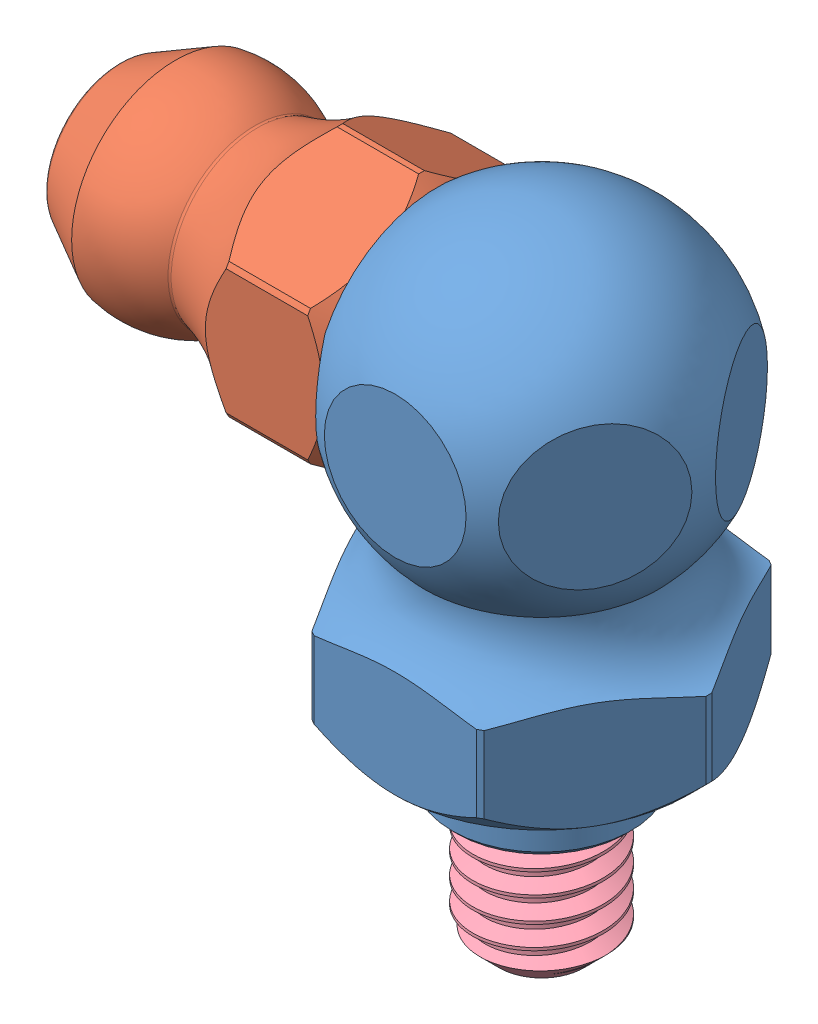
SolidWorks assembly Grease Nipple M8x1.0 H3 Mod, configuration Default. Lengths in mm.
Overall size (18.25 19.7 10).
4 component instances, 4 part files, 9 mates.
Components (placement in the parent):
- Grease Nipple M8x1.0 H3 Mod-1: Grease Nipple M8x1.0 H3 Mod [B M8x1.00] at origin size (10.29 15.75 10)
- Grease Nipple A-1: Grease Nipple A [A M6x0.75H3] at (-10.6548 0 0) x (0 1 0) z (0 0 1) size (8.34 14.3 7)
- Steel Ball-1: Steel Ball [Ø 2.50] at (-11.85 0 0) size (2.5 2.5 2.5)
- Brezon M8x1.0 H3 Mod-1: Brezon M8x1.0 H3 Mod [Default] at (0 -14.7 0) x (-1 0 0) z (0 -1 0) size (4.12 4.62 9)
Mates (geometry in assembly coordinates):
- Concentric1: concentric anti-aligned: cylinder of Grease Nipple M8x1.0 H3 Mod-1 through (-3.2 0 0) axis (-1 0 0) radius 2.625; cone of Grease Nipple A-1 through (1.1 0 0) axis (1 0 0)
- Coincident1: coincident anti-aligned: plane of Grease Nipple M8x1.0 H3 Mod-1 through (-3.2 0 0) normal (-1 0 0); plane of Grease Nipple A-1 through (-3.2 3.9915 0) normal (1 0 0)
- Parallel1: parallel aligned: plane of Grease Nipple M8x1.0 H3 Mod-1 through (0 0 0) normal (0 0 1); plane of Grease Nipple A-1 through (-10.6548 0 0) normal (0 0 1)
- Coincident2: coincident: circle of Grease Nipple A-1; sphere of Steel Ball-1
- Parallel2: parallel aligned: plane of Grease Nipple M8x1.0 H3 Mod-1 through (0 0 0) normal (0 0 1); plane of Steel Ball-1 through (-11.85 0 0) normal (0 0 1)
- Parallel3: parallel aligned: plane of Grease Nipple M8x1.0 H3 Mod-1 through (0 0 0) normal (0 1 0); plane of Steel Ball-1 through (-11.85 0 0) normal (0 1 0)
- Concentric2: concentric anti-aligned: cylinder of Grease Nipple M8x1.0 H3 Mod-1 through (0 25.9411 0) axis (0 1 0) radius 1.65; cylinder of Brezon M8x1.0 H3 Mod-1 through (0 -5.7 0) axis (0 -1 0) radius 2
- Distance1: distance = 4.2 mm aligned: plane of Grease Nipple M8x1.0 H3 Mod-1 through (2.75 -10.5 0) normal (0 -1 0); plane of Brezon M8x1.0 H3 Mod-1 through (0 -14.7 0) normal (0 -1 0)
- Parallel4: parallel anti-aligned: plane of Grease Nipple M8x1.0 H3 Mod-1 through (0 0 0) normal (0 0 1); plane of Brezon M8x1.0 H3 Mod-1 through (0 -14.7 0) normal (0 0 -1)
